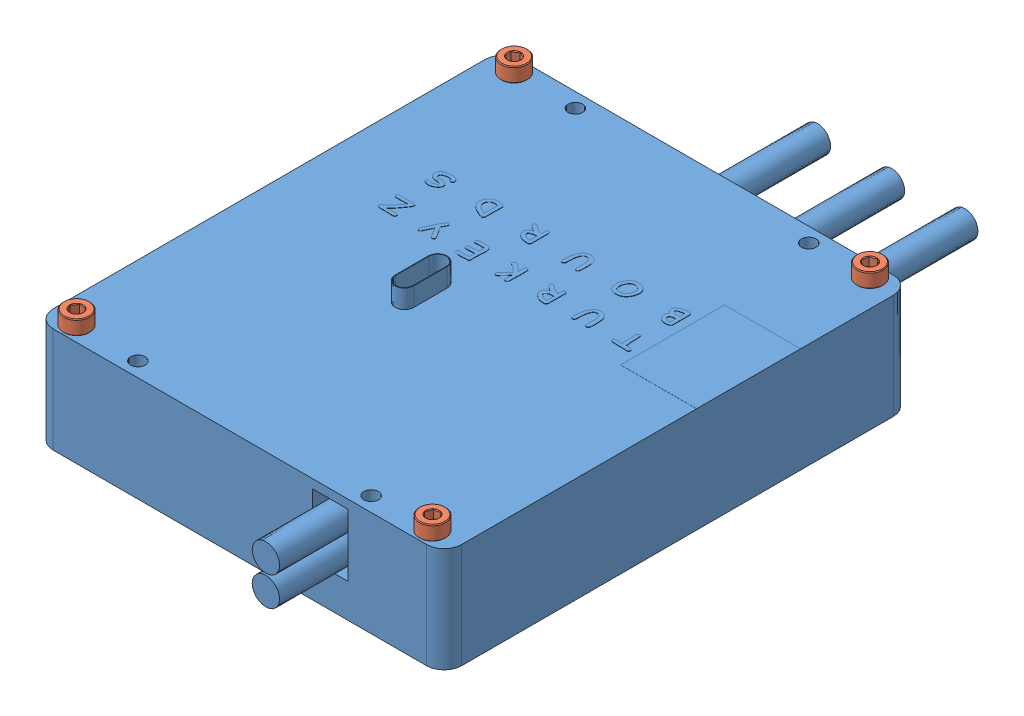
SolidWorks assembly TB6 complete with screwirex, configuration Default. Lengths in mm.
Overall size (70 21.2 110).
5 component instances, 2 part files, 8 mates.
Components (placement in the parent):
- TORQUERYBOX-1: TORQUERYBOX [Default] at (-25.3262 -10.7744 36.0974) size (70 21.2 110)
- M2.5 CLASS 12.9 SOCKET HEAD CAP SCREW-1: M2.5 CLASS 12.9 SOCKET HEAD CAP SCREW [91290A051] at (-20.8262 4.2256 33.5974) x (0.878816 0 -0.477161) z (0 -1 0) size (4.5 4.5 5.62)
- M2.5 CLASS 12.9 SOCKET HEAD CAP SCREW-2: M2.5 CLASS 12.9 SOCKET HEAD CAP SCREW [91290A051] at (40.1738 4.2256 33.5974) x (0.773146 0 -0.634228) z (0 -1 0) size (4.5 4.5 5.62)
- M2.5 CLASS 12.9 SOCKET HEAD CAP SCREW-4: M2.5 CLASS 12.9 SOCKET HEAD CAP SCREW [91290A051] at (40.1738 4.2256 -41.4026) x (0.618245 0 -0.785985) z (0 -1 0) size (4.5 4.5 5.62)
- M2.5 CLASS 12.9 SOCKET HEAD CAP SCREW-6: M2.5 CLASS 12.9 SOCKET HEAD CAP SCREW [91290A051] at (-20.8262 4.2256 -41.4026) x (0.416756 0 -0.909018) z (0 -1 0) size (4.5 4.5 5.62)
Mates (geometry in assembly coordinates):
- Concentric1: concentric aligned: cylinder of TORQUERYBOX-1 through (-20.8262 7.2256 33.5974) axis (0 -1 0) radius 1.25; cylinder of M2.5 CLASS 12.9 SOCKET HEAD CAP SCREW-1 through (-20.8262 9.7256 33.5974) axis (0 -1 0) radius 2.25
- Coincident1: coincident anti-aligned: plane of TORQUERYBOX-1 through (-22.3262 7.2256 33.0974) normal (0 1 0); plane of M2.5 CLASS 12.9 SOCKET HEAD CAP SCREW-1 through (-20.8262 7.2256 33.5974) normal (0 -1 0)
- Concentric2: concentric aligned: cylinder of TORQUERYBOX-1 through (40.1738 7.2256 33.5974) axis (0 -1 0) radius 1.25; cylinder of M2.5 CLASS 12.9 SOCKET HEAD CAP SCREW-2 through (40.1738 9.7256 33.5974) axis (0 -1 0) radius 2.25
- Coincident2: coincident anti-aligned: plane of TORQUERYBOX-1 through (-22.3262 7.2256 33.0974) normal (0 1 0); plane of M2.5 CLASS 12.9 SOCKET HEAD CAP SCREW-2 through (40.1738 7.2256 33.5974) normal (0 -1 0)
- Concentric3: concentric aligned: cylinder of TORQUERYBOX-1 through (40.1738 7.2256 -41.4026) axis (0 -1 0) radius 1.25; cylinder of M2.5 CLASS 12.9 SOCKET HEAD CAP SCREW-4 through (40.1738 9.7256 -41.4026) axis (0 -1 0) radius 2.25
- Coincident3: coincident anti-aligned: plane of TORQUERYBOX-1 through (-22.3262 7.2256 33.0974) normal (0 1 0); plane of M2.5 CLASS 12.9 SOCKET HEAD CAP SCREW-4 through (40.1738 7.2256 -41.4026) normal (0 -1 0)
- Concentric4: concentric aligned: cylinder of TORQUERYBOX-1 through (-20.8262 7.2256 -41.4026) axis (0 -1 0) radius 1.25; cylinder of M2.5 CLASS 12.9 SOCKET HEAD CAP SCREW-6 through (-20.8262 9.7256 -41.4026) axis (0 -1 0) radius 2.25
- Coincident4: coincident anti-aligned: plane of TORQUERYBOX-1 through (-22.3262 7.2256 33.0974) normal (0 1 0); plane of M2.5 CLASS 12.9 SOCKET HEAD CAP SCREW-6 through (-20.8262 7.2256 -41.4026) normal (0 -1 0)
